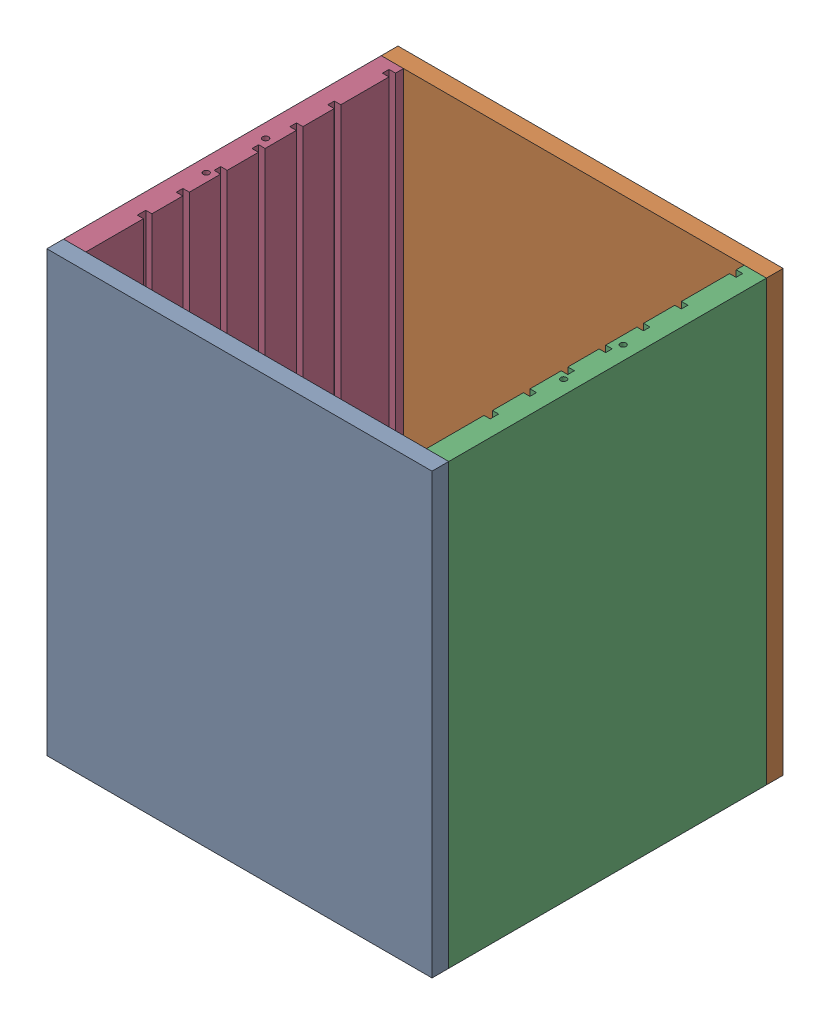
SolidWorks assembly CRT-CARD-CAGE, configuration Default. Lengths in mm.
Overall size (109.7 125 100).
4 component instances, 3 part files, 0 mates.
Components (placement in the parent):
- CAP-PLATE-1: CAP-PLATE [Default] at (117.8628 52.3805 167.2763) size (109.7 125 4.76)
- CAP-PLATE-2: CAP-PLATE [Default] at (116.3628 52.3805 72.7963) x (-1 0 0) z (0 0 -1) size (109.7 125 4.76)
- LH-SIDE-PLATE-1: LH-SIDE-PLATE [Default] at (66.6128 52.3805 120.0363) size (6.35 125 90.48)
- RH-SIDE_PLATE-1: RH-SIDE_PLATE [Default] at (-43.0872 52.3805 120.0363) size (6.35 125 90.48)
